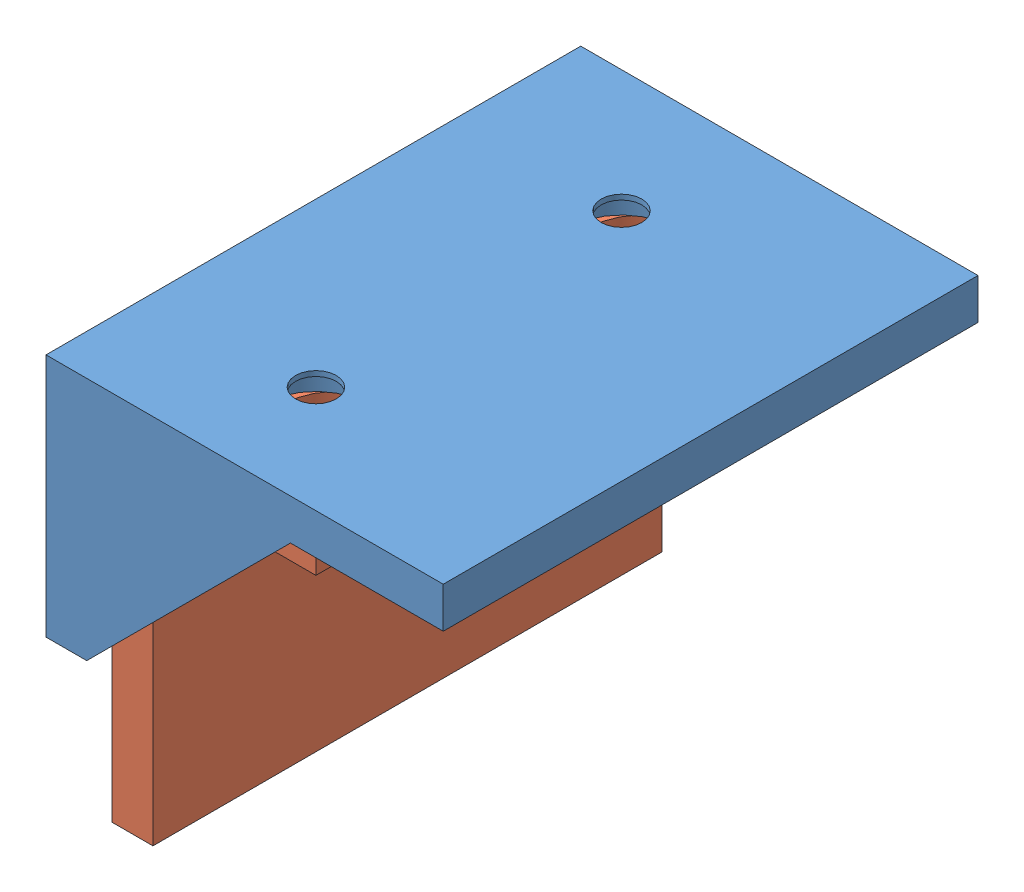
SolidWorks assembly Montagem1, configuration Valor predeterminado. Lengths in mm.
Overall size (39 39 52.5).
2 component instances, 2 part files, 3 mates.
Components (placement in the parent):
- basee-1: basee [Valor predeterminado] at (-14.9682 11.1884 26.25) size (39 24 52.5)
- ferramenta-1: ferramenta [Valor predeterminado] at (-10.9682 7.1884 26.25) size (20 35 50)
Mates (geometry in assembly coordinates):
- Coincidente1: coincident: plane of basee-1 through (-14.9682 11.1884 76.25) normal (0 -1 0); line of ferramenta-1 through (-14.9682 11.1884 76.25) axis (0 0 -1)
- Coincidente2: coincident anti-aligned: plane of basee-1 through (-14.9682 -8.8116 76.25) normal (1 0 0); plane of ferramenta-1 through (-14.9682 11.1884 76.25) normal (-1 0 0)
- Coincidente3: coincident anti-aligned: plane of basee-1 through (-14.9682 11.1884 76.25) normal (0 0 -1); plane of ferramenta-1 through (-10.9682 7.1884 76.25) normal (0 0 1)
